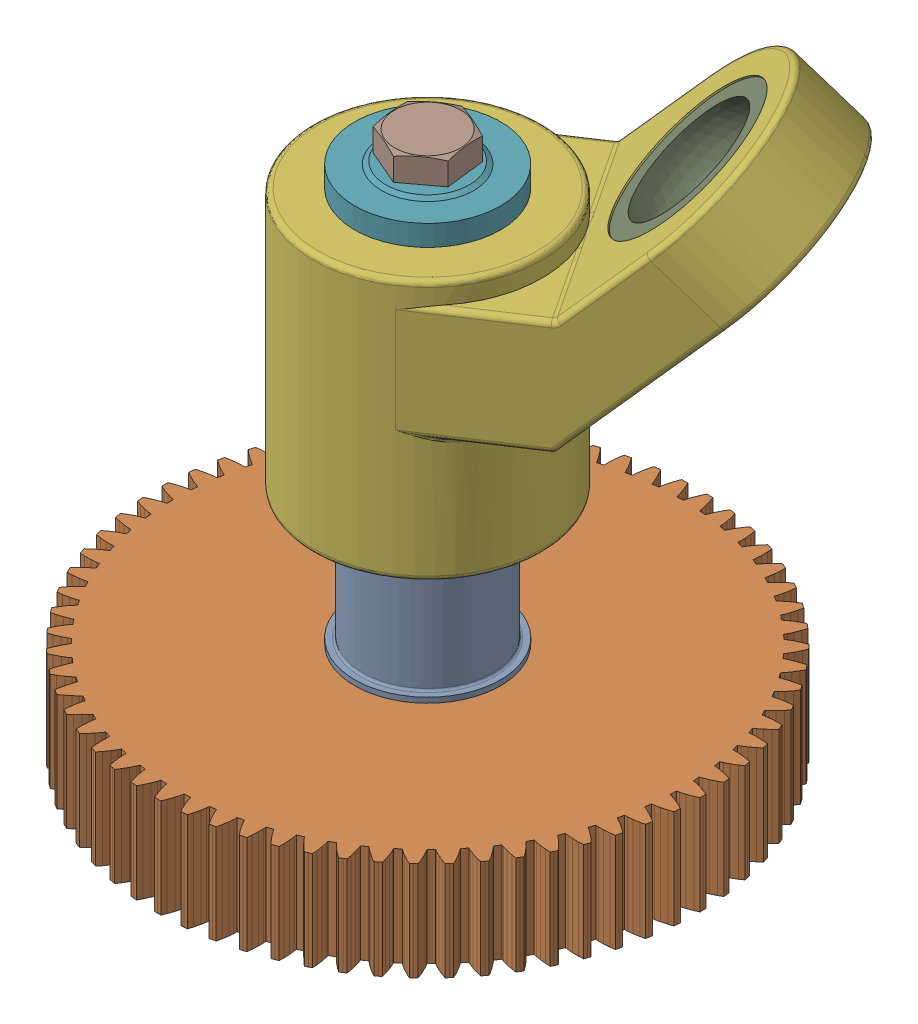
SolidWorks assembly Arbre de sortie, configuration Défaut. Lengths in mm.
Overall size (143.4 149.09 143.41).
9 component instances, 8 part files, 17 mates.
Components (placement in the parent):
- Arbre sortie reducteur-1: Arbre sortie reducteur [Défaut] at (31.5 122.8 31.5) x (0 -1 0) z (-0.551853 0 -0.833941) size (123.8 28 28)
- Roue denture droite m=1,5 mm z=67 b=19 mm-1: Roue denture droite m=1,5 mm z=67 b=19 mm [Défaut] at (31.5 29 31.5) x (0 1 0) z (-0.551853 0 -0.833941) size (19 103.47 103.49)
- Goupille A 6 x 16 - NF E 27-484-1: Goupille A 6 x 16 - NF E 27-484 [Défaut] at (24.6018 45 21.0757) x (0.934335 0 0.356395) z (0 -1 0) size (6 6 16)
- Goupille A 6 x 16 - NF E 27-484-2: Goupille A 6 x 16 - NF E 27-484 [Défaut] at (38.3982 45 41.9243) x (0.974446 0 0.224621) z (0 -1 0) size (6 6 16)
- Clavette parallele B, 6 x 6 x 38 mm - NF E 27-656-1: Clavette parallele B, 6 x 6 x 38 mm - NF E 27-656 [Défaut] at (26.0794 84.8 35.087) x (0 1 0) z (-0.833941 0 0.551853) size (38 6 6)
- Bras d'entrainement-1: Bras d'entrainement [Défaut] at (31.5 73.8 31.5) x (0.551853 0 0.833941) z (0 -1 0) size (44.02 83.29 74.29)
- Rondelle speciale-1: Rondelle speciale [Défaut] at (31.5 123.8 31.5) x (0 1 0) z (-0.265773 0 0.964036) size (4.5 28 28)
- Vis H M8-20 NF E 25-114-1: Vis H M8-20 NF E 25-114 [Défaut] at (31.5 128.3 31.5) x (0.993203 0 -0.116398) z (0 1 0) size (13 15.01 25.3)
- Rotule partie femelle-1: Rotule partie femelle [Défaut] at (64.6403 130.0606 9.5697) x (-0.696822 -0.689716 0.196805) z (-0.589686 0.707107 0.390219) size (30 30 10)
Mates (geometry in assembly coordinates):
- Coaxiale5: concentric aligned: cylinder of Arbre sortie reducteur-1 through (24.6018 29 21.0757) axis (0 -1 0) radius 3; cylinder of Roue denture droite m=1,5 mm z=67 b=19 mm-1 through (24.6018 29 21.0757) axis (0 -1 0) radius 3
- Coaxiale6: concentric anti-aligned: cylinder of Arbre sortie reducteur-1 through (31.5 123.8 31.5) axis (0 1 0) radius 12.5; cylinder of Roue denture droite m=1,5 mm z=67 b=19 mm-1 through (31.5 48 31.5) axis (0 -1 0) radius 12.5
- Coïncidente7: coincident aligned: plane of Arbre sortie reducteur-1 through (21.0757 29 38.3982) normal (0 -1 0); plane of Roue denture droite m=1,5 mm z=67 b=19 mm-1 through (31.5 29 31.5) normal (0 -1 0)
- Tangent4: tangent aligned: plane of Arbre sortie reducteur-1 through (21.0757 29 38.3982) normal (0 -1 0); sphere of Goupille A 6 x 16 - NF E 27-484-1
- Coaxiale10: concentric anti-aligned: cylinder of Arbre sortie reducteur-1 through (38.3982 29 41.9243) axis (0 -1 0) radius 3; cylinder of Goupille A 6 x 16 - NF E 27-484-2 through (38.3982 45 41.9243) axis (0 1 0) radius 3
- Tangent8: tangent aligned: plane of Arbre sortie reducteur-1 through (21.0757 29 38.3982) normal (0 -1 0); sphere of Goupille A 6 x 16 - NF E 27-484-2
- Coïncidente9: coincident anti-aligned: plane of Arbre sortie reducteur-1 through (26.0794 78.8 35.087) normal (-0.833941 0 0.551853); plane of Clavette parallele B, 6 x 6 x 38 mm - NF E 27-656-1 through (27.5142 122.8 37.2553) normal (0.833941 0 -0.551853)
- Coïncidente10: coincident anti-aligned: plane of Arbre sortie reducteur-1 through (27.7349 122.8 37.5889) normal (-0.551853 0 -0.833941); plane of Clavette parallele B, 6 x 6 x 38 mm - NF E 27-656-1 through (23.0649 122.8 40.6792) normal (0.551853 0 0.833941)
- Coïncidente11: coincident aligned: plane of Arbre sortie reducteur-1 through (31.5 122.8 31.5) normal (0 1 0); plane of Clavette parallele B, 6 x 6 x 38 mm - NF E 27-656-1 through (26.6679 122.8 41.4127) normal (0 1 0)
- Coaxiale12: concentric anti-aligned: cylinder of Arbre sortie reducteur-1 through (31.5 123.8 31.5) axis (0 1 0) radius 10; cylinder of Bras d'entrainement-1 through (31.5 123.8 31.5) axis (0 -1 0) radius 10
- Coïncidente13: coincident anti-aligned: plane of Arbre sortie reducteur-1 through (23.1606 75.8 37.0185) normal (0 1 0); plane of Bras d'entrainement-1 through (31.5 75.8 31.5) normal (0 -1 0)
- Coaxiale13: concentric aligned: cylinder of Arbre sortie reducteur-1 through (31.5 122.8 31.5) axis (0 1 0) radius 3.375; cylinder of Rondelle speciale-1 through (31.5 123.8 31.5) axis (0 1 0) radius 4.2
- Coaxiale14: concentric aligned: cylinder of Arbre sortie reducteur-1 through (31.5 122.8 31.5) axis (0 1 0) radius 3.375; cylinder of Vis H M8-20 NF E 25-114-1 through (31.5 128.9 31.5) axis (0 1 0) radius 4
- Coaxiale9: concentric anti-aligned: cylinder of Roue denture droite m=1,5 mm z=67 b=19 mm-1 through (24.6018 29 21.0757) axis (0 -1 0) radius 3; cylinder of Goupille A 6 x 16 - NF E 27-484-1 through (24.6018 45 21.0757) axis (0 1 0) radius 3
- Coïncidente12: coincident anti-aligned: plane of Clavette parallele B, 6 x 6 x 38 mm - NF E 27-656-1 through (23.0649 122.8 40.6792) normal (0.551853 0 0.833941); plane of Bras d'entrainement-1 through (22.4811 147.6701 41.0655) normal (-0.551853 0 -0.833941)
- Coïncidente14: coincident anti-aligned: plane of Bras d'entrainement-1 through (31.5 123.8 31.5) normal (0 1 0); plane of Rondelle speciale-1 through (31.5 123.8 31.5) normal (0 -1 0)
- Coïncidente15: coincident anti-aligned: plane of Rondelle speciale-1 through (31.5 128.3 31.5) normal (0 1 0); plane of Vis H M8-20 NF E 25-114-1 through (30.9064 128.3 26.4347) normal (0 -1 0)
